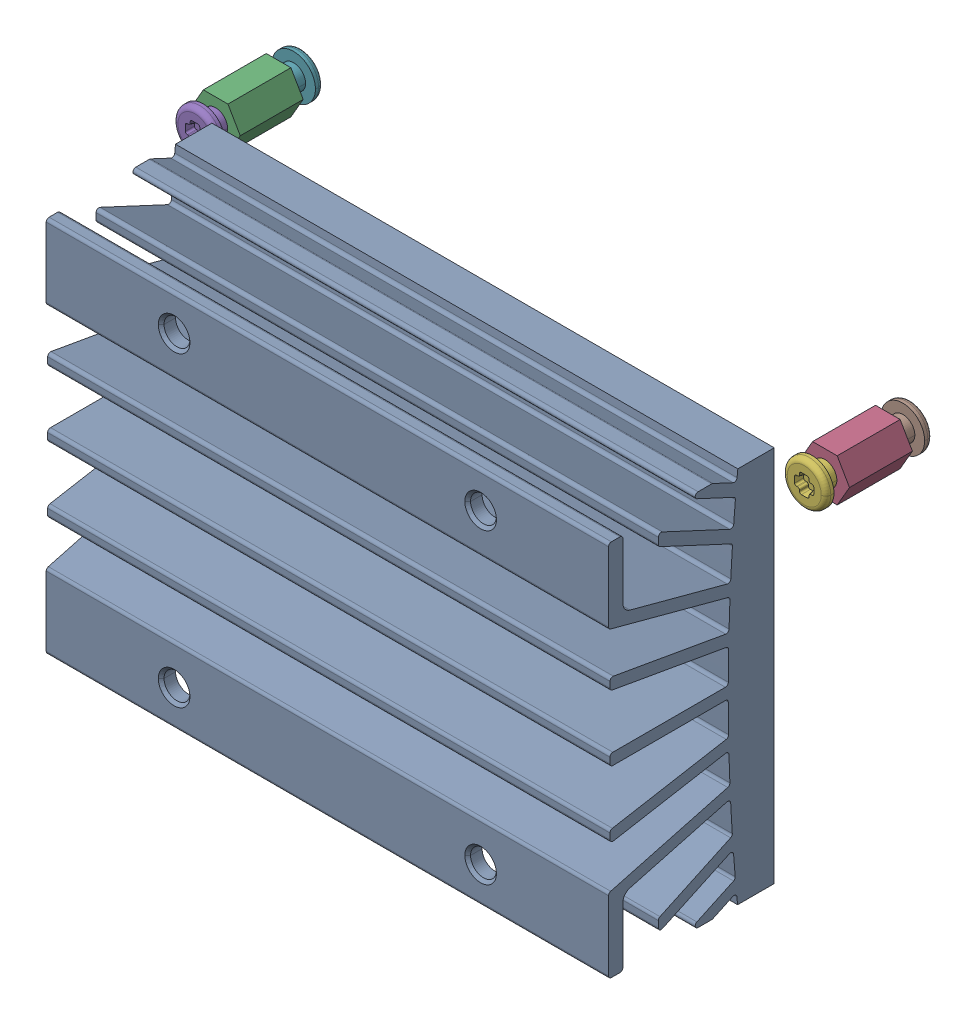
SolidWorks assembly 682-13450_PORG_ME_THER_ASSY, configuration 682-13450_PORG_ME_THER_ASSY. Lengths in mm.
Overall size (68.74 39.4 29.11).
13 component instances, 5 part files, 0 mates.
Components (placement in the parent):
- PORG_HSK_ASSY-1: PORG_HSK_ASSY [PORG_HSK_ASSY] at (11.2 22.5 12.2762) size (58.7 39.4 17.3)
  - 110-0111-000-1: 110-0111-000 [110-0111-000] at origin size (58.7 39.4 17.3)
- PORG_LEAF_SPRING_DRAWN-1: PORG_LEAF_SPRING_DRAWN [PORG_LEAF_SPRING_DRAWN] at (11.2001 22.4999 7.8662) x (1 0.000006 0) z (0 0 1) size (39.83 21.3 0.8)
- 155-0746-000-1: 155-0746-000 [155-0746-000] at (12.2 58.5 1.57) size (5.14 4.45 6.57)
- 155-0746-000-2: 155-0746-000 [155-0746-000] at (75.8 58.5 1.57) size (5.14 4.45 6.57)
- 155-0754-000-1: 155-0754-000 [155-0754-000] at (12.2 58.5 5.7662) x (-1 0 0) z (0 0 -1) size (4.55 4.55 4.53)
- 155-0754-000-2: 155-0754-000 [155-0754-000] at (75.8 58.5 5.7662) x (-1 0 0) z (0 0 -1) size (4.55 4.55 4.53)
- 155-0754-000-3: 155-0754-000 [155-0754-000] at (12.2 58.5 3.7) size (4.55 4.55 4.53)
- 155-0754-000-4: 155-0754-000 [155-0754-000] at (75.8 58.5 3.7) size (4.55 4.55 4.53)
- 155-0717-000-1: 155-0717-000 [155-0717-000] at (18.1871 28.4982 13.4762) x (0 0 -1) z (0 1 0) size (6.41 4.7 4.7)
- 155-0717-000-2: 155-0717-000 [155-0717-000] at (18.1871 43.4018 13.4762) x (0 0 -1) z (0 1 0) size (6.41 4.7 4.7)
- 155-0717-000-3: 155-0717-000 [155-0717-000] at (51.6129 43.4018 13.4762) x (0 0 -1) z (0 1 0) size (6.41 4.7 4.7)
- 155-0717-000-4: 155-0717-000 [155-0717-000] at (51.6129 28.4982 13.4762) x (0 0 -1) z (0 1 0) size (6.41 4.7 4.7)
